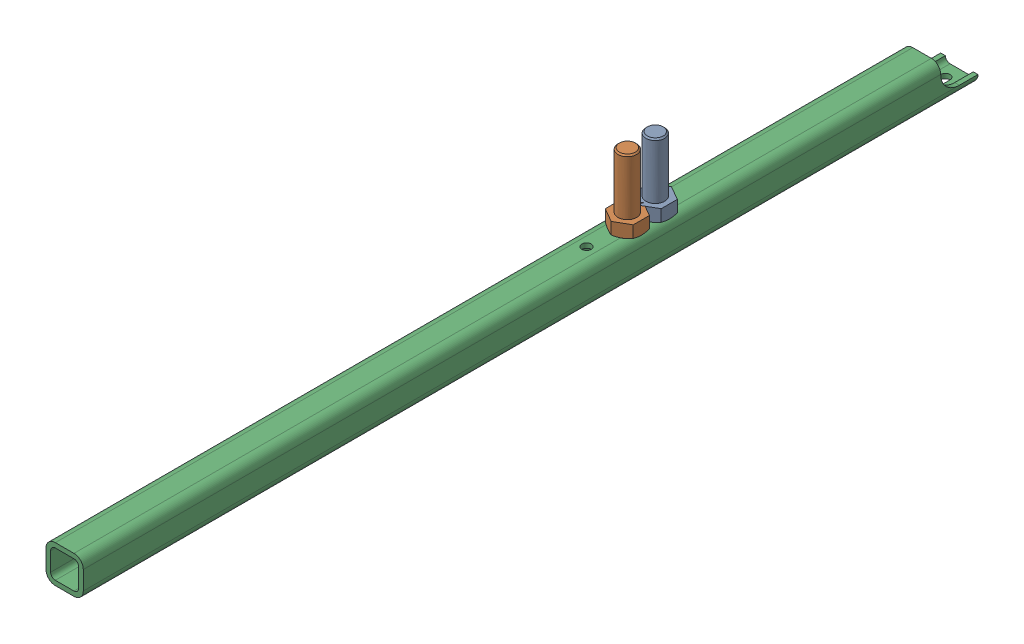
SolidWorks assembly 01-050-00-0-1, configuration Default. Lengths in mm.
Overall size (50.8 144.78 1219.2).
3 component instances, 2 part files, 0 mates.
Components (placement in the parent):
- hex bolt_ai(PreviewCfg)-1: hex bolt_ai(PreviewCfg) [Default] at (30.1625 50.8 -190.5) x (0 1 0) z (-1 0 0) size (93.98 43.99 38.1)
- hex bolt_ai(PreviewCfg)-2: hex bolt_ai(PreviewCfg) [Default] at (30.1625 50.8 -152.4) x (0 1 0) z (-1 0 0) size (93.98 43.99 38.1)
- 01-049-00-0-1: 01-049-00-0 [Default] at origin size (50.8 50.8 1219.2)
